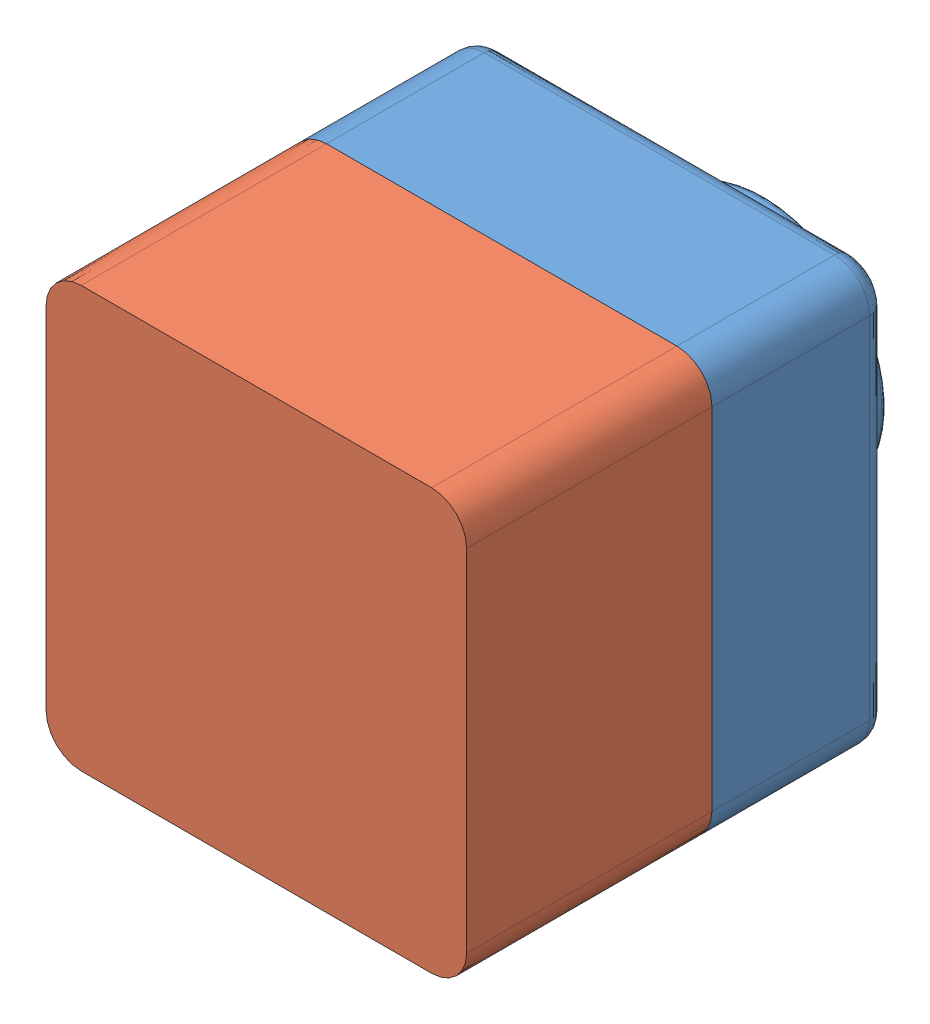
SolidWorks assembly Assem1, configuration Default. Lengths in mm.
Overall size (120 120 145).
2 component instances, 2 part files, 3 mates.
Components (placement in the parent):
- lil' practice-1: lil' practice [Default] at (-21.1795 137.0066 72.9894) size (120 120 75)
- Tutor 2-1: Tutor 2 [Default] at (69.0507 100.0245 192.9894) x (-1 0 0) z (0 0 -1) size (120 120 90)
Mates (geometry in assembly coordinates):
- Coincident2: coincident: plane of lil' practice-1 through (-21.1795 137.0066 122.9894) normal (0 0 1); plane of Tutor 2-1 through (38.8205 93.2628 122.9894) normal (0 0 -1)
- Coincident3: coincident: plane of lil' practice-1 through (-21.1795 137.0066 122.9894) normal (-1 0 0); plane of Tutor 2-1 through (-21.1795 137.0066 102.9894) normal (-1 0 0)
- Coincident4: coincident aligned: plane of lil' practice-1 through (-21.1795 137.0066 122.9894) normal (0 1 0); plane of Tutor 2-1 through (98.8205 137.0066 102.9894) normal (0 1 0)
